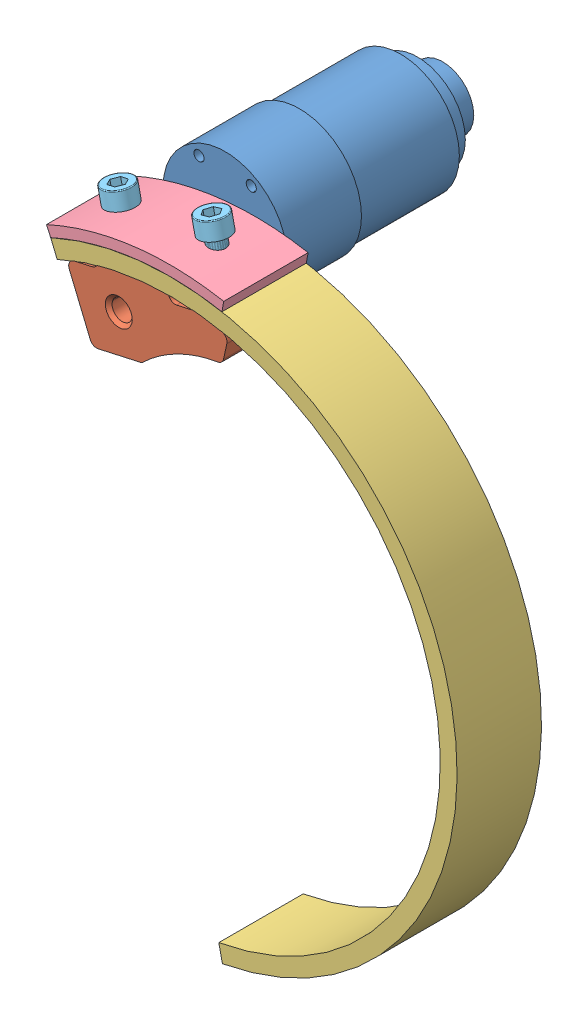
SolidWorks assembly robotex-leg-assembly, configuration Default. Lengths in mm.
Overall size (136.16 186.41 96).
7 component instances, 5 part files, 14 mates.
Components (placement in the parent):
- gearnotor_w_encoder-1: gearnotor_w_encoder [Default] at (-24.1852 2.5393 10.2871) size (36.8 36.8 86.5)
- simplelehholder-1: simplelehholder [Default] at (-8.9437 -72.7813 63.7871) x (0 0 -1) z (0.976008 0.217736 0) size (25 20.91 46.71)
- leg-prop-1: leg-prop [Default] at (-11.9959 -73.3461 38.7871) x (0 0 1) z (-0.983304 -0.181973 0) size (25 170 105.76)
- aluseib-1: aluseib [Default] at (-8.9437 -72.7813 63.7871) x (0 0 -1) z (0.983642 -0.180134 0) size (25 18.37 50.47)
- socket head cap screw_iso-1: socket head cap screw_iso [ISO 4762 M5 x 20 --- 20C] at (-9.2305 22.4409 51.2871) x (0.217736 -0.976008 0) z (-0.100654 -0.022455 -0.994668) size (25 8.5 8.5)
- socket head cap screw_iso-2: socket head cap screw_iso [ISO 4762 M5 x 20 --- 20C] at (-37.0404 16.2368 51.2871) x (0.217736 -0.976008 0) z (0 0 1) size (25 8.5 8.5)
- socket head cap screw_iso-3: socket head cap screw_iso [ISO 4762 M4 x 16 --- 16C] at (-20.9385 -19.0145 45.2871) x (-0.217736 0.976008 0) z (0 0 1) size (20 7 7)
Mates (geometry in assembly coordinates):
- Concentric1: concentric anti-aligned: cylinder of gearnotor_w_encoder-1 through (-24.1852 -4.4607 54.2871) axis (0 0 -1) radius 3; cylinder of simplelehholder-1 through (-24.1852 -4.4607 38.7871) axis (0 0 1) radius 3
- Coincident1: coincident anti-aligned: plane of gearnotor_w_encoder-1 through (-24.1852 -4.4607 38.7871) normal (0 0 1); plane of simplelehholder-1 through (-8.9437 -72.7813 38.7871) normal (0 0 -1)
- Concentric3: concentric anti-aligned: cylinder of simplelehholder-1 through (-8.9437 -72.7813 38.7871) axis (0 0 1) radius 80; cylinder of leg-prop-1 through (-8.9437 -72.7813 63.7871) axis (0 0 -1) radius 80
- Parallel2: parallel aligned: plane of simplelehholder-1 through (-8.9437 -72.7813 38.7871) normal (-0.923371 -0.38391 0); plane of leg-prop-1 through (-11.9959 -73.3461 63.7871) normal (-0.923371 -0.38391 0)
- Coincident5: coincident aligned: plane of simplelehholder-1 through (-8.9437 -72.7813 63.7871) normal (0 0 1); plane of leg-prop-1 through (-11.9959 -73.3461 63.7871) normal (0 0 1)
- Concentric4: concentric anti-aligned: cylinder of leg-prop-1 through (-8.9437 -72.7813 63.7871) axis (0 0 -1) radius 85; cylinder of aluseib-1 through (-8.9437 -72.7813 38.7871) axis (0 0 1) radius 85
- Coincident7: coincident aligned: plane of leg-prop-1 through (-11.9959 -73.3461 38.7871) normal (0 0 -1); plane of aluseib-1 through (-8.9437 -72.7813 38.7871) normal (0 0 -1)
- Coincident8: coincident anti-aligned: line of leg-prop-1 through (-44.3578 4.49 63.7871) axis (0 0 -1); line of aluseib-1 through (-44.3578 4.49 38.7871) axis (0 0 1)
- Concentric5: concentric anti-aligned: cylinder of aluseib-1 through (-5.6008 6.1706 51.2871) axis (0.217736 -0.976008 0) radius 2.5; cylinder of socket head cap screw_iso-1 through (-16.1436 53.4291 51.2871) axis (-0.217736 0.976008 0) radius 2.5
- Tangent1: tangent anti-aligned: cylinder of aluseib-1 through (-8.9437 -72.7813 38.7871) axis (0 0 1) radius 88; plane of socket head cap screw_iso-1 through (-12.2677 16.6404 51.7254) normal (0.217736 -0.976008 0)
- Concentric6: concentric aligned: cylinder of simplelehholder-1 through (-34.0276 2.7321 51.2871) axis (-0.217736 0.976008 0) radius 2.1; cylinder of socket head cap screw_iso-2 through (-43.9535 47.2251 51.2871) axis (-0.217736 0.976008 0) radius 2.5
- Tangent2: tangent anti-aligned: cylinder of aluseib-1 through (-8.9437 -72.7813 38.7871) axis (0 0 1) radius 88; plane of socket head cap screw_iso-2 through (-31.8037 12.2822 51.2871) normal (0.217736 -0.976008 0)
- Concentric7: concentric aligned: cylinder of simplelehholder-1 through (-21.8094 -15.1105 45.2871) axis (0.217736 -0.976008 0) radius 1.65; cylinder of socket head cap screw_iso-3 through (-14.0254 -50.0027 45.2871) axis (0.217736 -0.976008 0) radius 2
- Coincident9: coincident anti-aligned: plane of simplelehholder-1 through (-21.8094 -15.1105 38.7871) normal (0.217736 -0.976008 0); plane of socket head cap screw_iso-3 through (-25.2254 -15.8725 45.2871) normal (-0.217736 0.976008 0)
